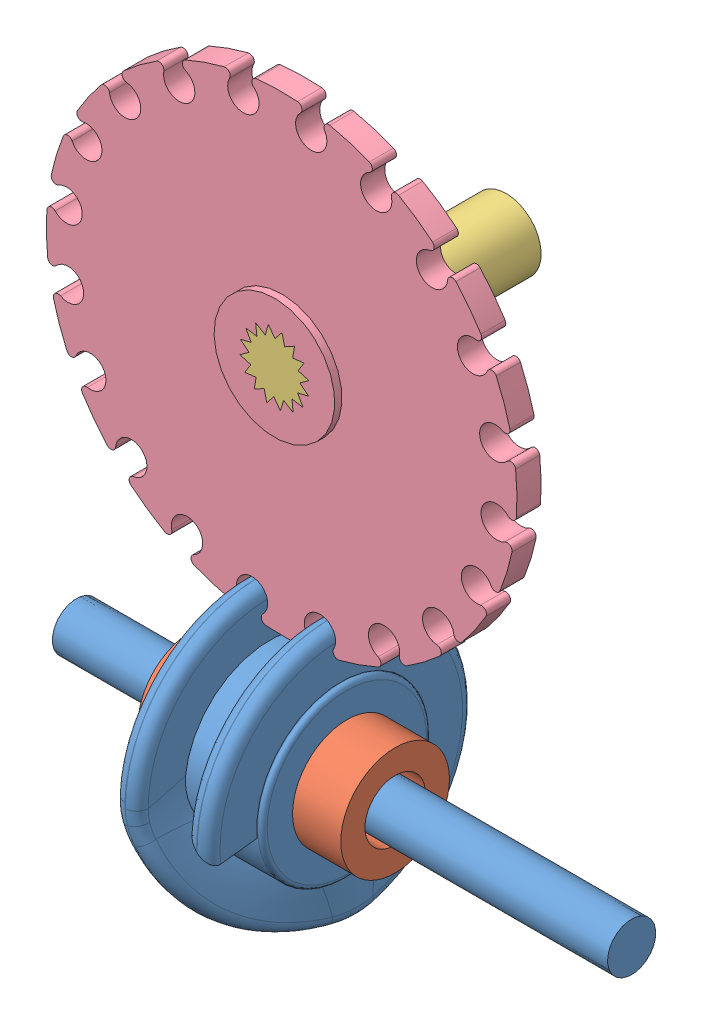
SolidWorks assembly intermittent mechansim assembly, configuration Default. Lengths in mm.
Overall size (275.8 341.85 151.9).
6 component instances, 5 part files, 12 mates.
Components (placement in the parent):
- input shaft-1: input shaft [Default] x (1 0 0) z (0 -0.993386 -0.114825) size (230 112.97 112.97)
- sleeve 2-1: sleeve 2 [Default] at (-32.01 0 0) x (0 0 -1) z (1 0 0) size (45 45 20)
- sleeve 2-2: sleeve 2 [Default] at (32.01 0 0) x (0 0 -1) z (1 0 0) size (45 45 20)
- 2. outer shaft-1: 2. outer shaft [Default] at (0 141.8 0) x (0.217568 0.976045 0) z (0 0 -1) size (29 29 96)
- outer shaft-1: outer shaft [Default] at (0 141.8 0) x (0.574523 0.818488 0) z (0 0 1) size (194.98 194.98 16)
- sleeve 1-1: sleeve 1 [Default] at (0 141.8 -18.01) size (50 50 20)
Mates (geometry in assembly coordinates):
- Concentric1: concentric anti-aligned: cylinder of input shaft-1 through (-90 0 0) axis (1 0 0) radius 10; cylinder of sleeve 2-1 through (-22.01 0 0) axis (-1 0 0) radius 12.51
- Distance1: distance = 0.01 mm: plane of sleeve 2-1 through (-22.01 0 0) normal (1 0 0); plane of input shaft-1 through (-22 -1.1483 9.9339) normal (-1 0 0)
- Concentric2: concentric anti-aligned: cylinder of input shaft-1 through (-90 0 0) axis (1 0 0) radius 10; cylinder of sleeve 2-2 through (42.01 0 0) axis (-1 0 0) radius 12.51
- Distance2: distance = 0.01 mm anti-aligned: plane of sleeve 2-2 through (22.01 0 0) normal (-1 0 0); plane of input shaft-1 through (22 -4.0189 34.7685) normal (1 0 0)
- Concentric3: concentric anti-aligned: cylinder of 2. outer shaft-1 through (0 141.8 -88) axis (0 0 1) radius 14.5; cylinder of outer shaft-1 through (0 141.8 8) axis (0 0 -1) radius 25
- Coincident4: coincident aligned: plane of 2. outer shaft-1 through (0 141.8 8) normal (0 0 1); plane of outer shaft-1 through (0 141.8 8) normal (0 0 1)
- Coincident5: coincident anti-aligned: plane of 2. outer shaft-1 through (-14.2826 139.2986 -8) normal (-0.276585 -0.960989 0); plane of outer shaft-1 through (-14.2826 139.2986 -8) normal (0.276585 0.960989 0)
- Coincident6: coincident aligned: plane of outer shaft-1 through (0 141.8 0) normal (0 0 1); plane of assembly through (0 0 0) normal (0 0 1)
- Coincident7: coincident aligned: plane of outer shaft-1; plane of assembly through (0 0 0) normal (1 0 0)
- Concentric4: concentric: cylinder of 2. outer shaft-1 through (0 141.8 -88) axis (0 0 1) radius 14.5; point of assembly
- Concentric5: concentric anti-aligned: cylinder of 2. outer shaft-1 through (0 141.8 -88) axis (0 0 1) radius 14.5; cylinder of sleeve 1-1 through (0 141.8 -8.01) axis (0 0 -1) radius 14.51
- Distance3: distance = 0.01 mm: plane of outer shaft-1 through (0 141.8 -8) normal (0 0 -1); plane of sleeve 1-1 through (0 141.8 -8.01) normal (0 0 1)
